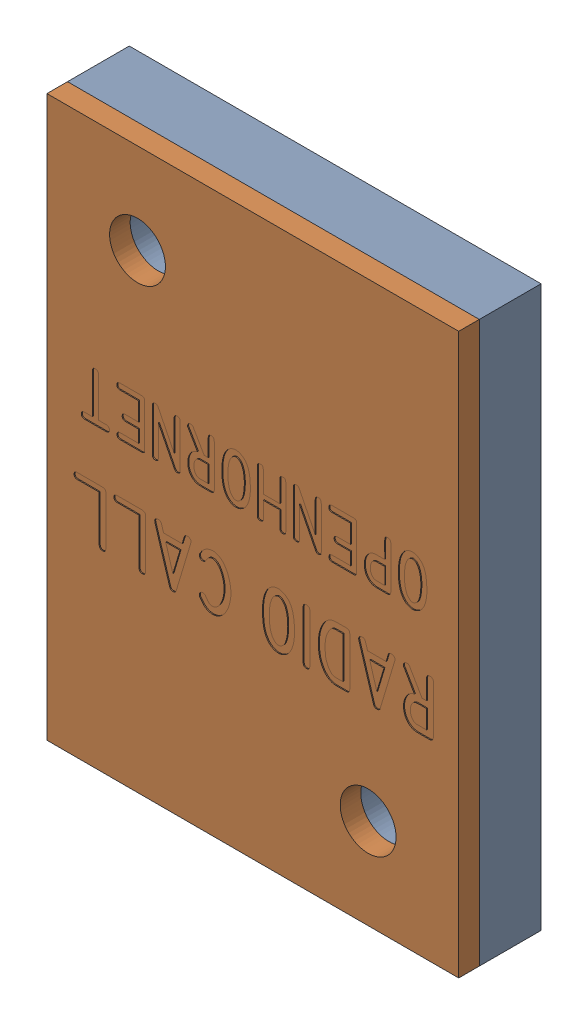
SolidWorks assembly BUNO Placard, configuration Default. Lengths in mm.
Overall size (31.75 43.18 6.35).
2 component instances, 2 part files, 0 mates.
Components (placement in the parent):
- BUNO Placard Lightplate-1: BUNO Placard Lightplate [Default] at origin size (31.75 43.18 4.76)
- BUNO Placard Legend Plate-1: BUNO Placard Legend Plate [Default] at (0 0 4.7625) size (31.75 43.18 1.59)
